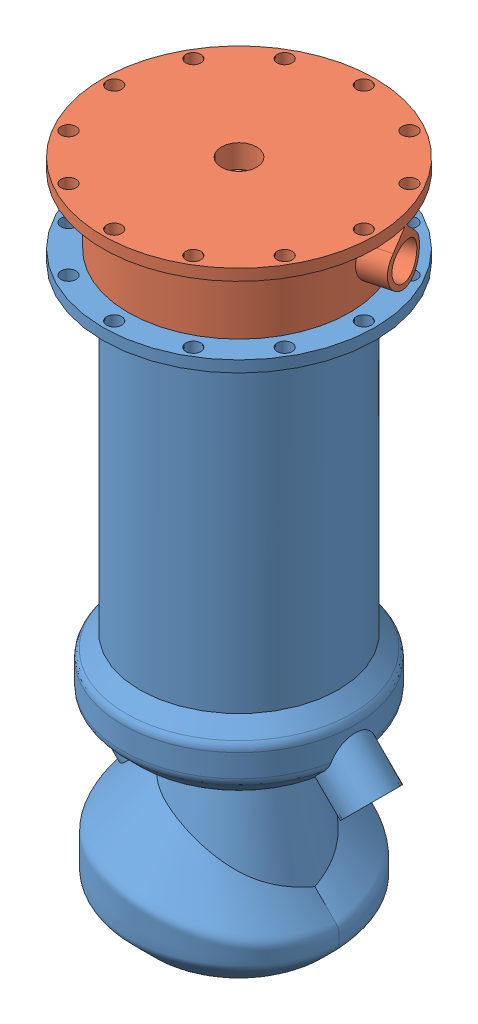
SolidWorks assembly regen additive coax swirl engine 2, configuration Default. Lengths in mm.
Overall size (208.18 407.94 208.18).
2 component instances, 2 part files, 4 mates.
Components (placement in the parent):
- slot cooling jacket 13-1: slot cooling jacket 13 [Default] at origin size (160.49 363.49 152.4)
- addative coax swirl injector4-1: addative coax swirl injector4 [Default] at (0 44.45 0) x (-0.866025 0 0.5) z (-0.5 0 -0.866025) size (152.4 50.8 152.4)
Mates (geometry in assembly coordinates):
- Coincident1: coordinate: point of slot cooling jacket 13-1
- Concentric1: concentric: cylinder of slot cooling jacket 13-1 through (0 -277.9245 0) axis (0 -1 0) radius 55.5625; cylinder of addative coax swirl injector4-1 through (0 -6.35 0) axis (0 -1 0) radius 61.9125
- Coincident2: coincident: plane of slot cooling jacket 13-1 through (-46.0375 0 0) normal (0 1 0); plane of addative coax swirl injector4-1 through (60.9921 0 10.6361) normal (0 -1 0)
- Concentric4: concentric aligned: cylinder of slot cooling jacket 13-1 through (60.4919 0 -34.925) axis (0 1 0) radius 4.2164; cylinder of addative coax swirl injector4-1 through (60.4919 44.45 -34.925) axis (0 1 0) radius 4.2164
